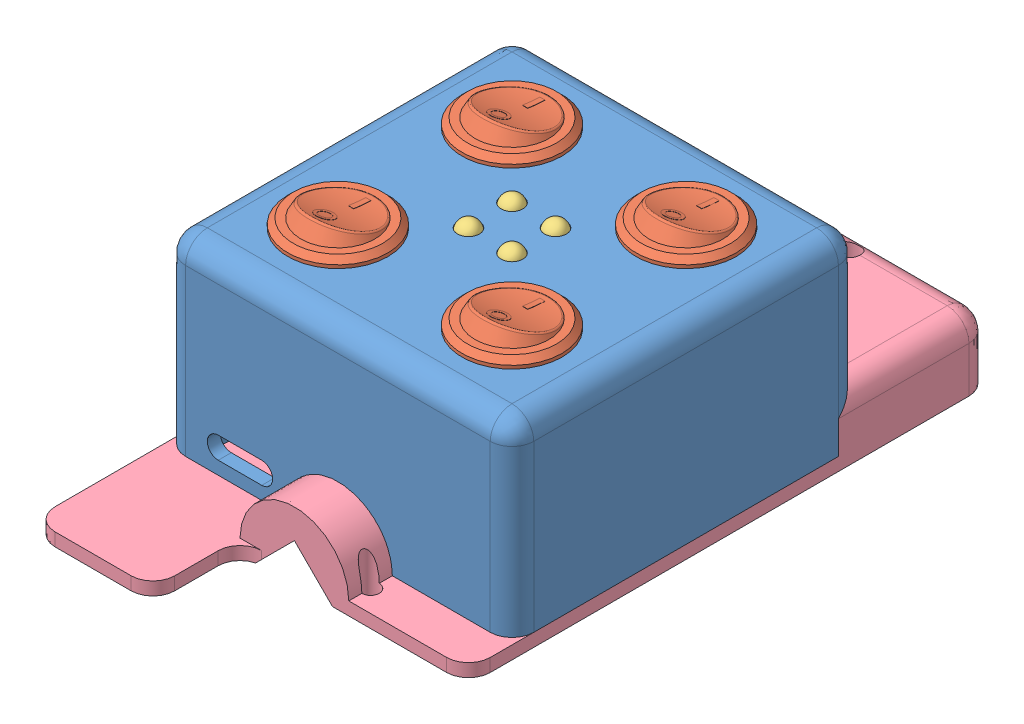
SolidWorks assembly Schalter-Pannel, configuration Standard. Lengths in mm.
Overall size (80 51.82 140).
10 component instances, 4 part files, 23 mates.
Components (placement in the parent):
- Pannel-1: Pannel [Standard] at (-0.4789 -2.6573 80) size (80 43 80)
- User Library-Arco Electric Switch R13112ABB-602AW_-1: User Library-Arco Electric Switch R13112ABB-602AW_ [Default] at (-20.4789 0.3427 120) x (1 0 0) z (0 1 0) size (23 23 28.42)
- User Library-Arco Electric Switch R13112ABB-602AW_-2: User Library-Arco Electric Switch R13112ABB-602AW_ [Default] at (19.5211 0.3427 120) x (1 0 0) z (0 1 0) size (23 23 28.42)
- User Library-Arco Electric Switch R13112ABB-602AW_-3: User Library-Arco Electric Switch R13112ABB-602AW_ [Default] at (19.5211 0.3427 80) x (1 0 0) z (0 1 0) size (23 23 28.42)
- User Library-Arco Electric Switch R13112ABB-602AW_-4: User Library-Arco Electric Switch R13112ABB-602AW_ [Default] at (-20.4789 0.3427 80) x (1 0 0) z (0 1 0) size (23 23 28.42)
- LED 5mm-1: LED 5mm [Valor predeterminado] at (4.5211 -6.6573 95) x (1 0 0) z (0 1 0) size (5.5 6 35.8)
- LED 5mm-2: LED 5mm [Valor predeterminado] at (-5.4789 -6.6573 105) x (1 0 0) z (0 1 0) size (5.5 6 35.8)
- LED 5mm-3: LED 5mm [Valor predeterminado] at (-5.4789 -6.6573 95) x (1 0 0) z (0 1 0) size (5.5 6 35.8)
- LED 5mm-4: LED 5mm [Valor predeterminado] at (4.5211 -6.6573 105) x (1 0 0) z (0 1 0) size (5.5 6 35.8)
- Pannel-Boden-1: Pannel-Boden [Standard] at (-40.4789 -45.6573 170) size (80 15.5 140)
Mates (geometry in assembly coordinates):
- Konzentrisch1: concentric anti-aligned: cylinder of Pannel-1 through (-20.4789 0.3427 80) axis (0 -1 0) radius 10.1; cylinder of User Library-Arco Electric Switch R13112ABB-602AW_-4 through (-20.4789 -14.1573 80) axis (0 1 0) radius 9.5
- Konzentrisch2: concentric anti-aligned: cylinder of Pannel-1 through (19.5211 0.3427 80) axis (0 -1 0) radius 10.1; cylinder of User Library-Arco Electric Switch R13112ABB-602AW_-3 through (19.5211 -14.1573 80) axis (0 1 0) radius 9.5
- Konzentrisch3: concentric anti-aligned: cylinder of Pannel-1 through (-20.4789 0.3427 120) axis (0 -1 0) radius 10.1; cylinder of User Library-Arco Electric Switch R13112ABB-602AW_-1 through (-20.4789 -14.1573 120) axis (0 1 0) radius 9.5
- Konzentrisch4: concentric anti-aligned: cylinder of Pannel-1 through (19.5211 0.3427 120) axis (0 -1 0) radius 10.1; cylinder of User Library-Arco Electric Switch R13112ABB-602AW_-2 through (19.5211 -14.1573 120) axis (0 1 0) radius 9.5
- Parallel1: parallel anti-aligned: plane of Pannel-1 through (29.561 0.3427 121.1) normal (0 0 -1); plane of User Library-Arco Electric Switch R13112ABB-602AW_-2 through (30.3211 -2.6573 121) normal (0 0 1)
- Parallel2: parallel anti-aligned: plane of Pannel-1 through (29.561 0.3427 81.1) normal (0 0 -1); plane of User Library-Arco Electric Switch R13112ABB-602AW_-3 through (30.3211 -2.6573 81) normal (0 0 1)
- Parallel3: parallel anti-aligned: plane of Pannel-1 through (-10.439 0.3427 81.1) normal (0 0 -1); plane of User Library-Arco Electric Switch R13112ABB-602AW_-4 through (-9.6789 -2.6573 81) normal (0 0 1)
- Parallel4: parallel anti-aligned: plane of Pannel-1 through (-10.439 0.3427 121.1) normal (0 0 -1); plane of User Library-Arco Electric Switch R13112ABB-602AW_-1 through (-9.6789 -2.6573 121) normal (0 0 1)
- Deckungsgleich5: coincident anti-aligned: plane of Pannel-1 through (-0.4789 0.3427 80) normal (0 1 0); plane of User Library-Arco Electric Switch R13112ABB-602AW_-1 through (-20.4789 0.3427 120) normal (0 -1 0)
- Deckungsgleich6: coincident aligned: plane of Pannel-1 through (-0.4789 0.3427 80) normal (0 1 0); circle of User Library-Arco Electric Switch R13112ABB-602AW_-2
- Deckungsgleich7: coincident anti-aligned: plane of Pannel-1 through (-0.4789 0.3427 80) normal (0 1 0); plane of User Library-Arco Electric Switch R13112ABB-602AW_-3 through (19.5211 0.3427 80) normal (0 -1 0)
- Deckungsgleich8: coincident anti-aligned: plane of Pannel-1 through (-0.4789 0.3427 80) normal (0 1 0); plane of User Library-Arco Electric Switch R13112ABB-602AW_-4 through (-20.4789 0.3427 80) normal (0 -1 0)
- Konzentrisch5: concentric anti-aligned: cylinder of Pannel-1 through (-5.4789 -19.6573 105) axis (0 1 0) radius 2.5; cylinder of LED 5mm-2 through (-5.4789 -5.6573 105) axis (0 -1 0) radius 2.5
- Konzentrisch6: concentric anti-aligned: cylinder of Pannel-1 through (4.5211 -19.6573 105) axis (0 1 0) radius 2.5; cylinder of LED 5mm-4 through (4.5211 -5.6573 105) axis (0 -1 0) radius 2.5
- Konzentrisch7: concentric anti-aligned: cylinder of Pannel-1 through (-5.4789 -19.6573 95) axis (0 1 0) radius 2.5; cylinder of LED 5mm-3 through (-5.4789 -5.6573 95) axis (0 -1 0) radius 2.5
- Konzentrisch8: concentric anti-aligned: cylinder of Pannel-1 through (4.5211 -19.6573 95) axis (0 1 0) radius 2.5; cylinder of LED 5mm-1 through (4.5211 -5.6573 95) axis (0 -1 0) radius 2.5
- Deckungsgleich9: coincident anti-aligned: plane of Pannel-1 through (-5.4789 -5.6573 95) normal (0 -1 0); circle of LED 5mm-3
- Deckungsgleich10: coincident anti-aligned: plane of Pannel-1 through (-5.4789 -5.6573 105) normal (0 -1 0); circle of LED 5mm-2
- Deckungsgleich11: coincident anti-aligned: plane of Pannel-1 through (4.5211 -5.6573 95) normal (0 -1 0); circle of LED 5mm-1
- Deckungsgleich12: coincident anti-aligned: plane of Pannel-1 through (4.5211 -5.6573 105) normal (0 -1 0); circle of LED 5mm-4
- Deckungsgleich13: coincident anti-aligned: plane of Pannel-1 through (-0.4789 -42.6573 137) normal (0 0 -1); plane of Pannel-Boden-1 through (-37.4789 -39.6573 137) normal (0 0 1)
- Deckungsgleich14: coincident anti-aligned: plane of Pannel-1 through (36.5211 -42.6573 80) normal (-1 0 0); plane of Pannel-Boden-1 through (36.5211 -39.6573 137) normal (1 0 0)
- Deckungsgleich15: coincident anti-aligned: plane of Pannel-1 through (-0.4789 -42.6573 80) normal (0 -1 0); plane of Pannel-Boden-1 through (-40.4789 -42.6573 170) normal (0 1 0)
